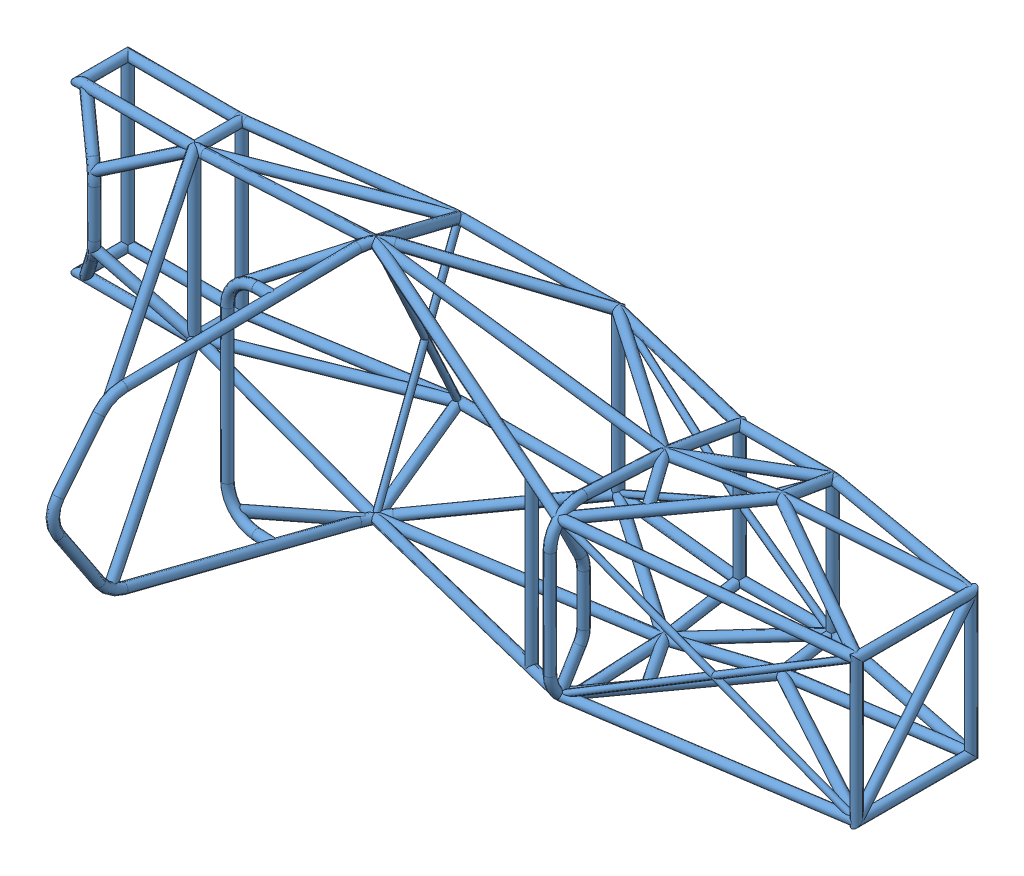
SolidWorks assembly Geometry, configuration Default. Lengths in mm.
Overall size (2330.4 1340.5 1077.7).
3 component instances, 3 part files, 3 mates.
Components (placement in the parent):
- Front Geometry-1: Front Geometry [Default] at origin size (495 1340.5 485)
- Rear Geometry-1: Rear Geometry [Default] at (-1550 0 0) size (310 1340.5 406.4)
- Frame-1: Frame [Default<As Machined>] at origin size (2330.4 661.74 1035.4)
Mates (geometry in assembly coordinates):
- Coincident1: coordinate: unknown of Front Geometry-1
- Coincident2: coordinate: unknown of Rear Geometry-1
- Coincident3: coordinate: unknown of Frame-1
